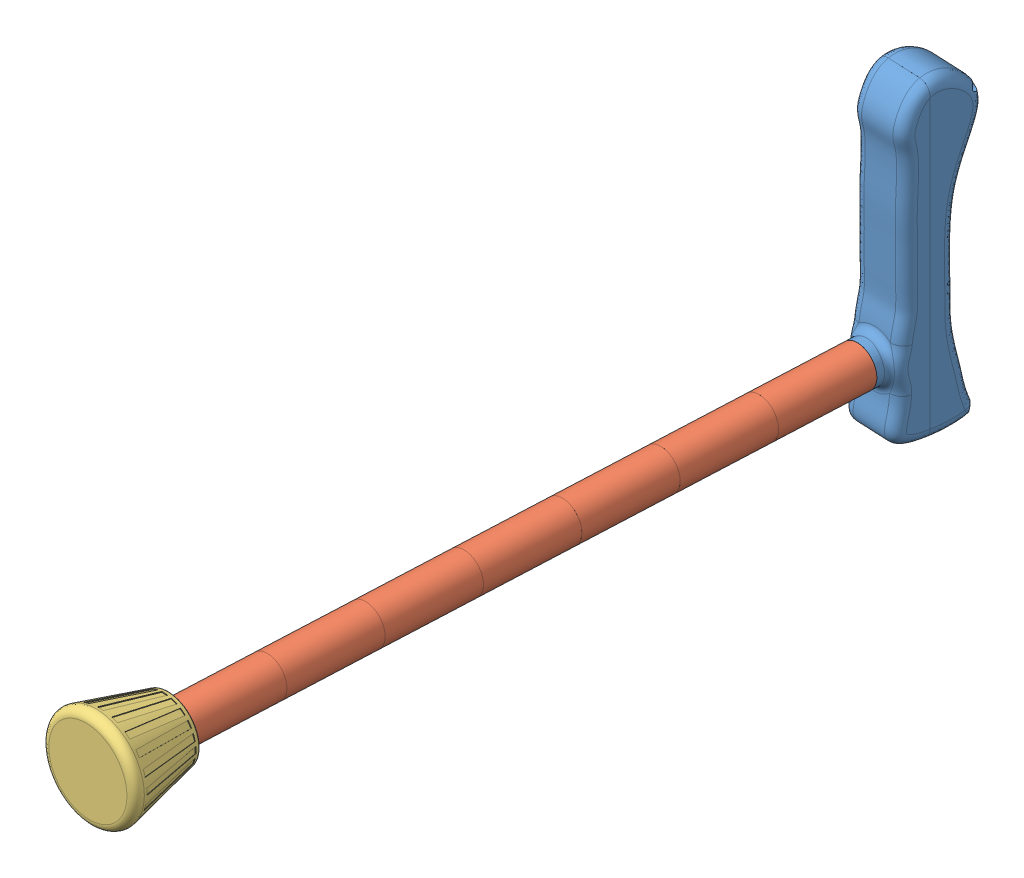
SolidWorks assembly 拐杖完整-cdh, configuration 默认. Lengths in mm.
Overall size (101.49 234.73 555.98).
9 component instances, 3 part files, 11 mates.
Components (placement in the parent):
- 把手-整体-1: 把手-整体 [Default] at (-6.9811 0 -91.0849) x (0.998942 0 0.045989) z (0 1 0) size (55.89 83.54 234.73)
- 长杆x60-1: 长杆x60 [默认] at (-22.5255 0.376 246.5575) x (-0.991405 0.12261 -0.045642) z (0.12248 0.992455 0.005639) size (25 69.5 25)
- 拐杖底-1: 拐杖底 [Default] at (-25.2848 0.376 306.494) x (0.545428 0.837781 0.02511) z (-0.836895 0.546006 -0.038529) size (62.19 59.5 62.19)
- 长杆x60-2: 长杆x60 [默认] at (-14.2474 0.376 66.7479) x (-0.991405 0.12261 -0.045642) z (0.12248 0.992455 0.005639) size (25 69.5 25)
- 长杆x60-8: 长杆x60 [默认] at (-17.0068 0.376 126.6845) x (-0.991405 0.12261 -0.045642) z (0.12248 0.992455 0.005639) size (25 69.5 25)
- 长杆x60-9: 长杆x60 [默认] at (-11.4881 0.376 6.8114) x (-0.736668 0.675404 -0.033915) z (0.674689 0.737448 0.031061) size (25 69.5 25)
- 长杆x60-10: 长杆x60 [默认] at (-19.7661 0.376 186.621) x (-0.991405 0.12261 -0.045642) z (0.12248 0.992455 0.005639) size (25 69.5 25)
- 长杆x60-11: 长杆x60 [默认] at (-8.7287 0.376 -53.1251) x (-0.991405 0.12261 -0.045642) z (0.12248 0.992455 0.005639) size (25 69.5 25)
- 长杆x60-12: 长杆x60 [默认] at (-5.9694 0.376 -113.0616) x (-0.706213 0.707253 -0.032513) z (0.706505 0.706961 0.032526) size (25 69.5 25)
Mates (geometry in assembly coordinates):
- 同心1: concentric anti-aligned: circle of 长杆x60-1; circle of 拐杖底-1
- 重合3: coincident aligned: circle of 长杆x60-2; circle of 长杆x60-8
- 重合4: coincident aligned: circle of 长杆x60-8; circle of 长杆x60-10
- 重合5: coincident anti-aligned: plane of 长杆x60-1 through (-25.2848 0.376 306.494) normal (-0.045989 0 0.998942); plane of 拐杖底-1 through (-25.2848 0.376 306.494) normal (0.045989 0 -0.998942)
- 重合6: coincident anti-aligned: plane of 长杆x60-1 through (-22.5255 0.376 246.5575) normal (0.045989 0 -0.998942); plane of 长杆x60-10 through (-22.5255 0.376 246.5575) normal (-0.045989 0 0.998942)
- 重合7: coincident aligned: circle of 长杆x60-1; circle of 长杆x60-10
- 重合8: coincident aligned: circle of 长杆x60-2; circle of 长杆x60-9
- 重合9: coincident aligned: circle of 长杆x60-9; circle of 长杆x60-11
- 重合10: coincident aligned: circle of 长杆x60-11; circle of 长杆x60-12
- 重合11: coincident anti-aligned: circle of 把手-整体-1; circle of 长杆x60-12
- 重合12: coincident aligned: plane of 把手-整体-1 through (-6.9811 0 -91.0849) normal (0 1 0)
